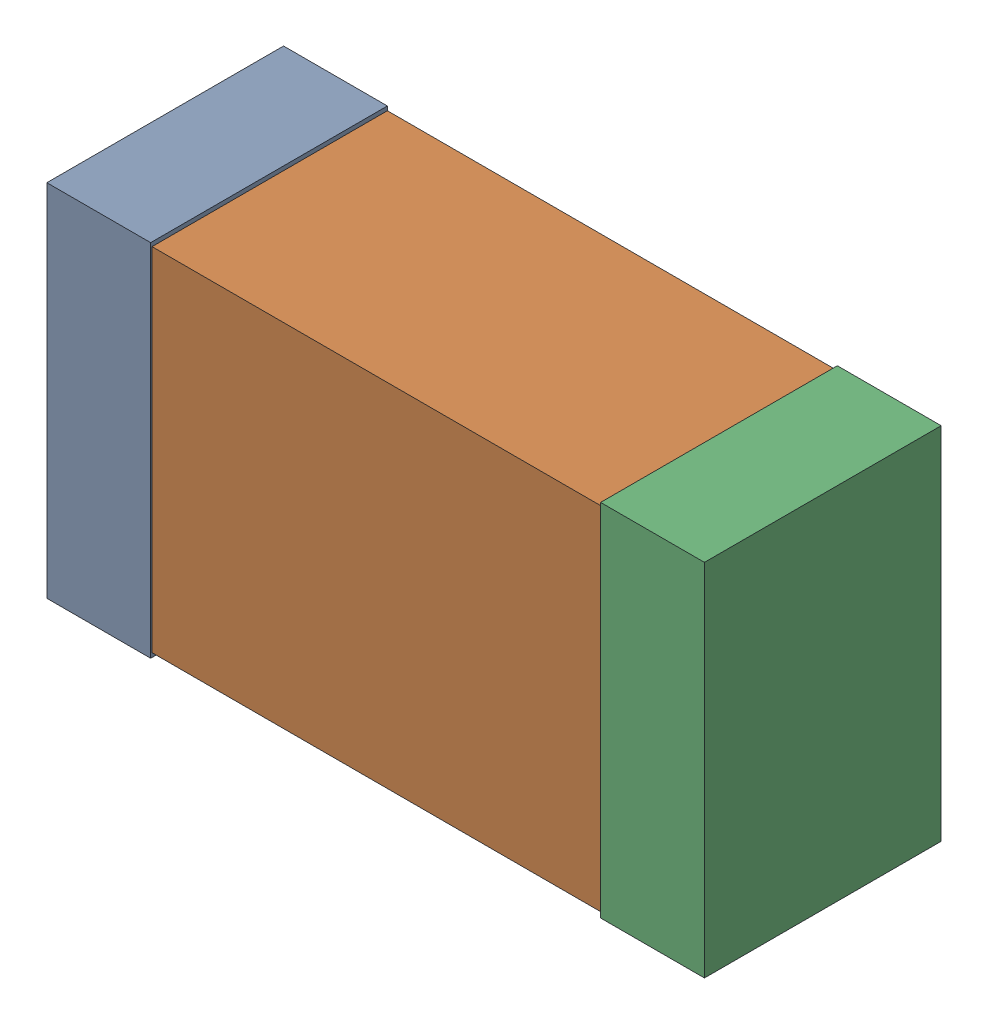
SolidWorks assembly C9_Motor_3Kanaloa_v2.0.0_Motor, configuration Default. Lengths in mm.
Overall size (2.38 1.3 0.85).
6 component instances, 2 part files, 0 mates.
Components (placement in the parent):
- 352877648-1: 352877648 [Default] at (34.247 78.232 0) size (0.38 1.3 0.85)
  - Extruded_14-1: Extruded_14 [Default] at origin size (0.38 1.3 0.85)
- 352877392-1: 352877392 [Default] at (35.247 78.232 0) size (2.2 1.27 0.85)
  - Extruded_15-1: Extruded_15 [Default] at origin size (2.2 1.27 0.85)
- 352877648-2: 352877648 [Default] at (36.247 78.232 0) size (0.38 1.3 0.85)
  - Extruded_14-1: Extruded_14 [Default] at origin size (0.38 1.3 0.85)
